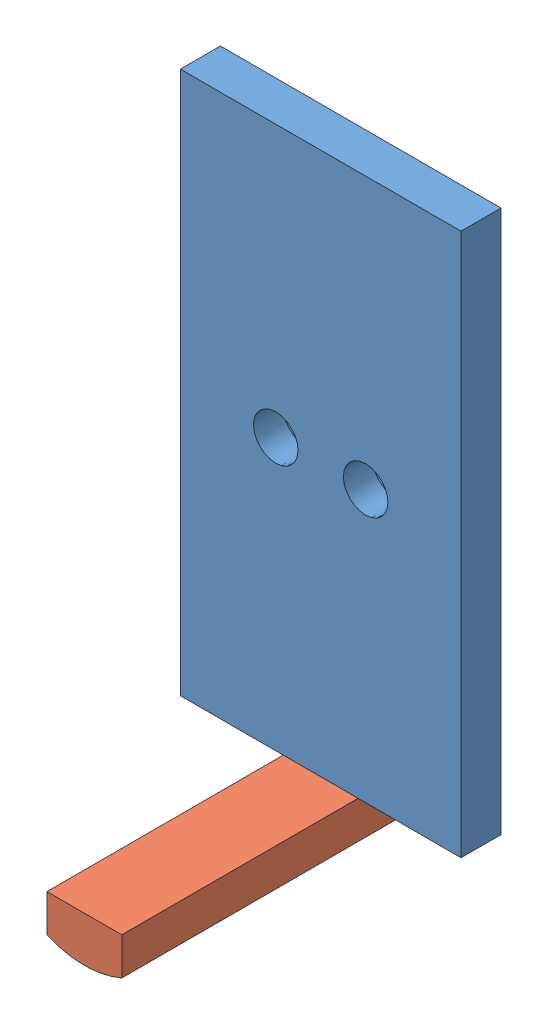
SolidWorks assembly MontagemHaste, configuration Valor predeterminado. Lengths in mm.
Overall size (75 157.09 75).
2 component instances, 2 part files, 2 mates.
Components (placement in the parent):
- Suporte-1: Suporte [Valor predeterminado] at (2.6928 6.155 145) size (75 145 10.7)
- HasteLinearPontaCirc-1: HasteLinearPontaCirc [Valor predeterminado] at (2.6928 -71.345 143.85) x (-1 0 0) z (0 0 1) size (20 12.09 75)
Mates (geometry in assembly coordinates):
- Concêntrico1: concentric: cylinder of Suporte-1 through (2.6928 -66.345 150.35) axis (0 -1 0) radius 3.3147; cylinder of HasteLinearPontaCirc-1 through (2.6928 -76.345 150.35) axis (0 -1 0) radius 3.175
- Coincidente1: coincident anti-aligned: plane of Suporte-1 through (40.1928 -66.345 155.7) normal (0 -1 0); plane of HasteLinearPontaCirc-1 through (-7.3072 -66.345 218.85) normal (0 1 0)
